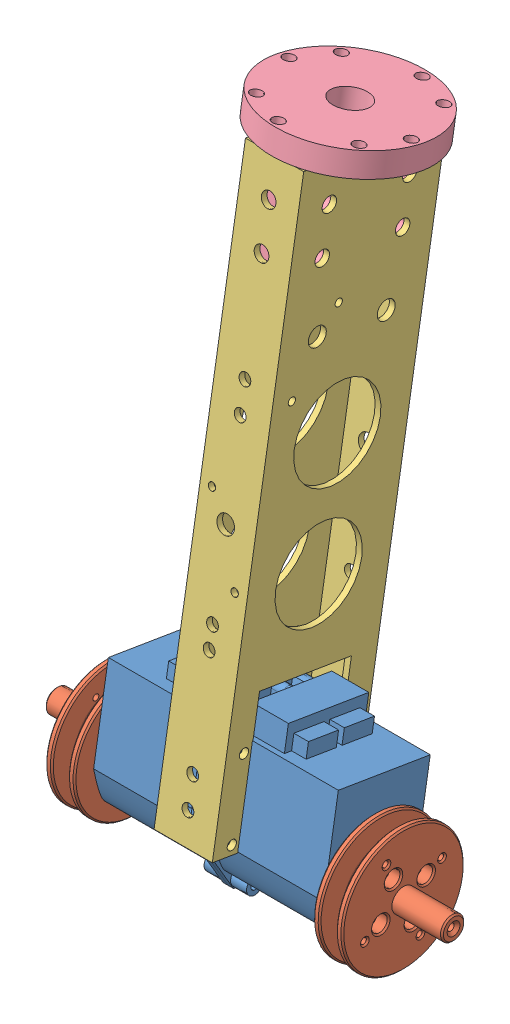
SolidWorks assembly link3, configuration 默认. Lengths in mm.
Overall size (136.4 234.26 91.77).
14 component instances, 9 part files, 9 mates.
Components (placement in the parent):
- Shoulder_Joint_Fix_L_ASS-1: Shoulder_Joint_Fix_L_ASS [默认] at (-8.5883 9.1785 14) size (80 71.53 44) (hidden)
  - Shoulder_Joint_Fix_L-1: Shoulder_Joint_Fix_L [默认] at (-2.8963 -28.6407 70) size (80 53 44)
  - Shoulder_Joint_Fix_BC_L-2: Shoulder_Joint_Fix_BC_L [默认] at (-25.8963 -28.6407 70) x (0 0 1) z (1 0 0) size (28 15 16)
  - Shoulder_Joint_Fix_Pulley_3_10_4-1: Shoulder_Joint_Fix_Pulley_3_10_4 [默认] at (-30.8963 -40.6407 88) x (-0.923728 -0.383049 0) z (0.383049 -0.923728 0) size (10 4 10)
  - Shoulder_Joint_Fix_Pulley_3_10_4-2: Shoulder_Joint_Fix_Pulley_3_10_4 [默认] at (-30.8963 -40.6407 56) x (-0.923728 -0.383049 0) z (0.383049 -0.923728 0) size (10 4 10)
  - Shoulder_Joint_Fix_Axis_3_38-1: Shoulder_Joint_Fix_Axis_3_38 [默认] at (-30.8963 -40.6407 70) x (0 0 1) z (0.923728 0.383049 0) size (38 3 3)
- Shoulder_Joint_2_Motor_ASS-1: Shoulder_Joint_2_Motor_ASS [默认] at (-0.3415 -22.9237 86.8584) x (0 -0.163076 -0.986613) z (0 0.986613 -0.163076) size (58.13 136.4 67.57)
  - MOTOR-1: MOTOR [默认] at (-4.5514 -19.483 61.2) size (42.7 46 56.4)
  - MOTOR-2: MOTOR [默认] at (-4.5514 -19.483 61.2) x (-1 0 0) z (0 0 1) size (42.7 46 56.4)
  - motor_a_gear_42mm_PBA_V2_1-1: motor_a_gear_42mm_PBA_V2_1 [默认] at (-4.5514 -65.483 46.1) x (0 1 0) z (-0.546944 0 0.837169) size (27.2 42 42)
  - motor_a_gear_42mm_PBA_V2_1-2: motor_a_gear_42mm_PBA_V2_1 [默认] at (-4.5514 26.517 46.1) x (0 -1 0) z (-0.546944 0 0.837169) size (27.2 42 42)
- Shoulder_Joint_AX_basement_square-1: Shoulder_Joint_AX_basement_square [默认] at (3.5154 -19.4621 84) x (1 0 0) z (0 0 -1) size (44 5.5 44) (hidden)
- Shoulder_Joint_Fix_ARM_UPPER-1: Shoulder_Joint_Fix_ARM_UPPER [默认] at (19.1415 22.0848 83.8294) x (0 -0.163076 -0.986613) z (1 0 0) size (50 192.5 20)
- ARM_CON_WS_V0_0_20160822-1: ARM_CON_WS_V0_0_20160822 [默认] at (19.1415 219.9008 51.1326) x (0 -0.163076 -0.986613) z (-1 0 0) size (52 40 52)
Mates (geometry in assembly coordinates):
- 同心10: concentric anti-aligned: cylinder of Shoulder_Joint_Fix_L_ASS-1/Shoulder_Joint_Fix_L-1 through (3.5154 -16.4621 84) axis (0 -1 0) radius 13.75; cylinder of Shoulder_Joint_AX_basement_square-1 through (3.5154 -26.4621 84) axis (0 1 0) radius 9
- 重合14: coincident anti-aligned: plane of Shoulder_Joint_Fix_L_ASS-1/Shoulder_Joint_Fix_L-1 through (-11.4846 -19.4621 84) normal (0 -1 0); plane of Shoulder_Joint_AX_basement_square-1 through (3.5154 -19.4621 84) normal (0 1 0)
- 重合15: coincident aligned: plane of Shoulder_Joint_Fix_L_ASS-1/Shoulder_Joint_Fix_L-1 through (-51.4846 -16.4621 106) normal (0 0 1); plane of Shoulder_Joint_AX_basement_square-1 through (-18.4846 -24.9621 106) normal (0 0 1)
- 同心28: concentric aligned: cylinder of Shoulder_Joint_2_Motor_ASS-1/MOTOR-1 through (11.8415 28.0942 101.7898) axis (1 0 0) radius 2.85; cylinder of Shoulder_Joint_Fix_ARM_UPPER-1 through (9.1415 28.0942 101.7898) axis (1 0 0) radius 1.6
- 距离12: distance = 11.8 mm anti-aligned: plane of Shoulder_Joint_Fix_ARM_UPPER-1 through (9.1415 216.0848 77.1026) normal (-1 0 0); plane of Shoulder_Joint_2_Motor_ASS-1/MOTOR-2 through (20.9415 38.1993 81.3686) normal (1 0 0)
- 角度1: planar angle = 0 rad aligned: plane of Shoulder_Joint_Fix_ARM_UPPER-1 through (9.1415 216.0848 77.1026) normal (0 0.163076 0.986613); plane of Shoulder_Joint_2_Motor_ASS-1/MOTOR-2 through (20.9415 26.8817 104.8789) normal (0 0.163076 0.986613)
- 重合18: coincident anti-aligned: plane of Shoulder_Joint_Fix_ARM_UPPER-1 through (11.1415 215.7587 75.1293) normal (1 0 0); plane of ARM_CON_WS_V0_0_20160822-1 through (11.1415 212.0079 52.4372) normal (-1 0 0)
- 重合19: coincident anti-aligned: plane of Shoulder_Joint_Fix_ARM_UPPER-1 through (19.1415 212.0079 52.4372) normal (0 0.986613 -0.163076); plane of ARM_CON_WS_V0_0_20160822-1 through (19.1415 212.0079 52.4372) normal (0 -0.986613 0.163076)
- 重合20: coincident anti-aligned: plane of Shoulder_Joint_Fix_ARM_UPPER-1 through (11.1415 215.7587 75.1293) normal (0 -0.163076 -0.986613); plane of ARM_CON_WS_V0_0_20160822-1 through (19.1415 215.7587 75.1293) normal (0 0.163076 0.986613)
